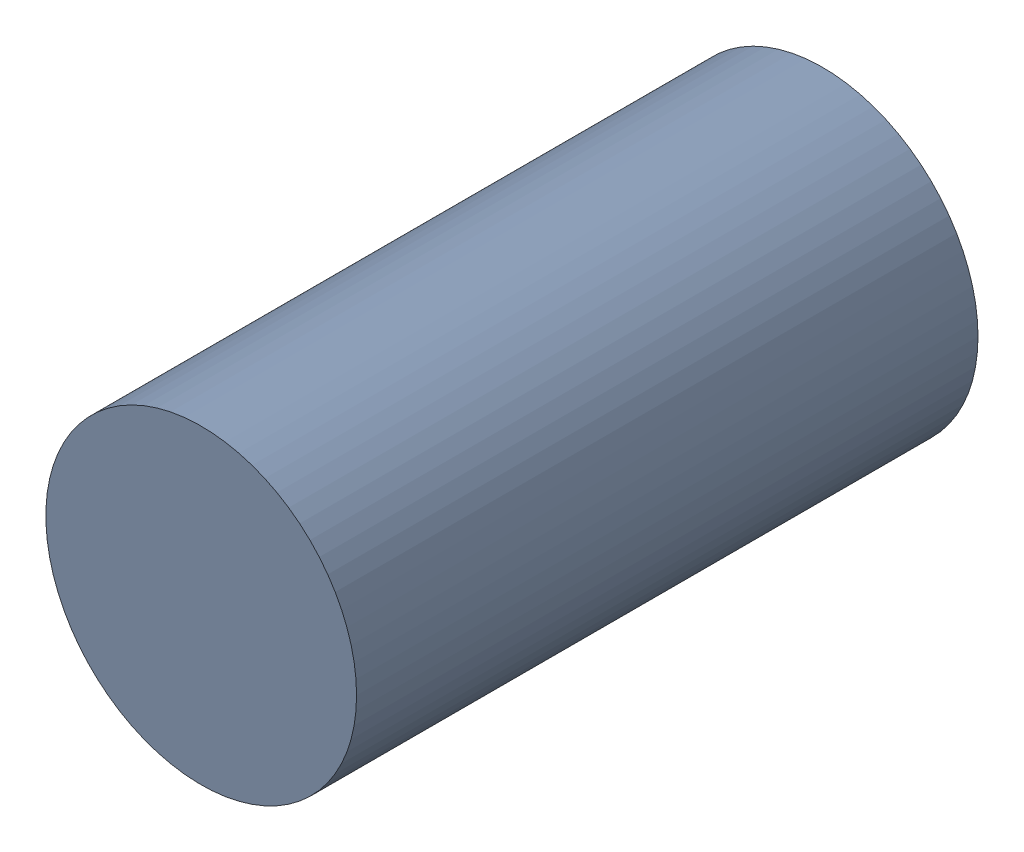
SolidWorks assembly MH12, configuration Default. Lengths in mm.
Overall size (1 1 2).
2 component instances, 1 part files, 0 mates.
Components (placement in the parent):
- 9228463120-1: 9228463120 [Default] at (144.979 80.6107 -1.5) size (1 1 2)
  - Cylinder-1: Cylinder [Default] at origin size (1 1 2)
